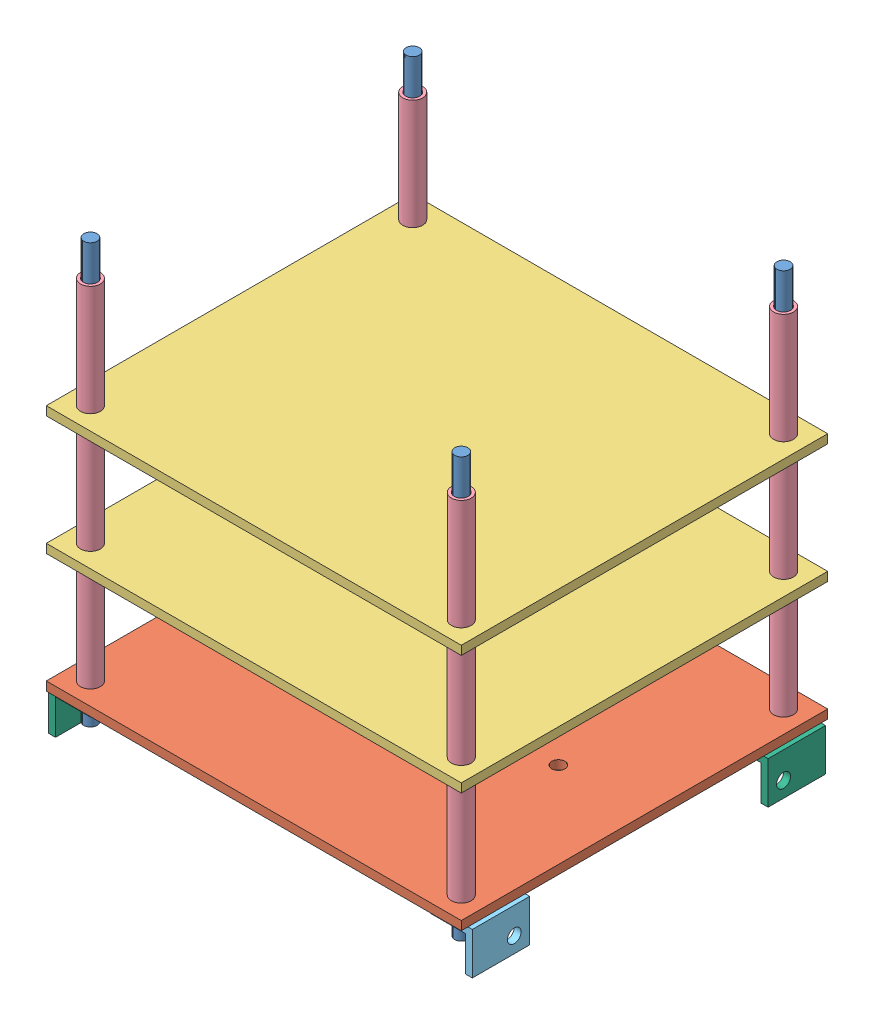
SolidWorks assembly PCB_Stack_3, configuration Default. Lengths in mm.
Overall size (96 98.53 83).
23 component instances, 6 part files, 64 mates.
Components (placement in the parent):
- PCB_Rod_2-1: PCB_Rod_2 [Default] at origin size (3 95 3)
- PCB_Rod_2-2: PCB_Rod_2 [Default] at (-84 0 0.0003) x (-0.139284 0 0.990253) z (-0.990253 0 -0.139284) size (3 95 3)
- PCB_Rod_2-3: PCB_Rod_2 [Default] at (-83.9998 0 73.0003) x (0.037489 0 0.999297) z (-0.999297 0 0.037489) size (3 95 3)
- PCB_Rod_2-4: PCB_Rod_2 [Default] at (0.0002 0 73) x (0.981991 0 -0.188925) z (0.188925 0 0.981991) size (3 95 3)
- PCB_Battery-1: PCB_Battery [Default] at (-41.9999 6 36.5001) x (-1 0 0.000003) z (-0.000003 0 -1) size (94 2 83)
- PCB-1: PCB [Default] at (-41.9999 60 36.5001) x (1 0 -0.000003) z (0.000003 0 1) size (94 2 83)
- PCB-2: PCB [Default] at (-41.9999 33 36.5001) x (1 0 -0.000003) z (0.000003 0 1) size (94 2 83)
- Aluminum Unthreaded Spacer_Battery-1: Aluminum Unthreaded Spacer_Battery [94669A105] at (0 20.5 0) x (0.317635 0 -0.948213) z (0 1 0) size (4.5 4.5 25)
- Aluminum Unthreaded Spacer_Battery-2: Aluminum Unthreaded Spacer_Battery [94669A105] at (0 47.5 0) x (0.317635 0 -0.948213) z (0 1 0) size (4.5 4.5 25)
- Aluminum Unthreaded Spacer_Battery-3: Aluminum Unthreaded Spacer_Battery [94669A105] at (0 74.5 0) x (-0.841831 0 -0.539741) z (0 1 0) size (4.5 4.5 25)
- Aluminum Unthreaded Spacer_Battery-4: Aluminum Unthreaded Spacer_Battery [94669A105] at (0.0002 20.5 73) x (0.317635 0 -0.948213) z (0 1 0) size (4.5 4.5 25)
- Aluminum Unthreaded Spacer_Battery-5: Aluminum Unthreaded Spacer_Battery [94669A105] at (0.0002 47.5 73) x (0.317635 0 -0.948213) z (0 1 0) size (4.5 4.5 25)
- Aluminum Unthreaded Spacer_Battery-6: Aluminum Unthreaded Spacer_Battery [94669A105] at (0.0002 74.5 73) x (-0.286549 0 -0.958066) z (0 1 0) size (4.5 4.5 25)
- Aluminum Unthreaded Spacer_Battery-7: Aluminum Unthreaded Spacer_Battery [94669A105] at (-83.9998 20.5 73.0003) x (0.317635 0 -0.948213) z (0 1 0) size (4.5 4.5 25)
- Aluminum Unthreaded Spacer_Battery-8: Aluminum Unthreaded Spacer_Battery [94669A105] at (-83.9998 47.5 73.0003) x (0.317635 0 -0.948213) z (0 1 0) size (4.5 4.5 25)
- Aluminum Unthreaded Spacer_Battery-9: Aluminum Unthreaded Spacer_Battery [94669A105] at (-83.9998 74.5 73.0003) x (-0.883236 0 -0.468929) z (0 1 0) size (4.5 4.5 25)
- Aluminum Unthreaded Spacer_Battery-10: Aluminum Unthreaded Spacer_Battery [94669A105] at (-84 47.5 0.0003) x (0.317635 0 -0.948213) z (0 1 0) size (4.5 4.5 25)
- Aluminum Unthreaded Spacer_Battery-11: Aluminum Unthreaded Spacer_Battery [94669A105] at (-84 74.5 0.0003) x (-0.872408 0 -0.488777) z (0 1 0) size (4.5 4.5 25)
- Aluminum Unthreaded Spacer_Battery-12: Aluminum Unthreaded Spacer_Battery [94669A105] at (-84 20.5 0.0003) x (0.317635 0 -0.948213) z (0 1 0) size (4.5 4.5 25)
- 88805K144_Architectural 6063 Aluminum 90 Degree Angle-1: 88805K144_Architectural 6063 Aluminum 90 Degree Angle [88805K144] at (-85.2375 1.2375 3.0003) x (-1 0 0.000003) z (0.000003 0 1) size (9.53 9.53 13)
- 88805K144_Architectural 6063 Aluminum 90 Degree Angle-2: 88805K144_Architectural 6063 Aluminum 90 Degree Angle [88805K144] at (1.2377 1.2375 70) x (0 1 0) z (0.000003 0 1) size (9.53 9.53 13)
- PCB_Bracket_1_(88805K144_Architectural 6063 Aluminum 90 Degree Angle)-1: PCB_Bracket_1_(88805K144_Architectural 6063 Aluminum 90 Degree Angle) [88805K144] at (1.2375 1.2375 3) x (0 1 0) z (0.000003 0 1) size (9.53 9.53 13)
- PCB_Bracket_1_(88805K144_Architectural 6063 Aluminum 90 Degree Angle)-2: PCB_Bracket_1_(88805K144_Architectural 6063 Aluminum 90 Degree Angle) [88805K144] at (-85.2373 1.2375 70.0003) x (0 1 0) z (-0.000003 0 -1) size (9.53 9.53 13)
Mates (geometry in assembly coordinates):
- Concentric1: concentric aligned: cylinder of PCB_Rod_2-1 through (0 95 0) axis (0 -1 0) radius 1.5; cylinder of PCB_Battery-1 through (0 7 0) axis (0 -1 0) radius 1.5
- Concentric2: concentric aligned: cylinder of PCB_Rod_2-4 through (0.0002 95 73) axis (0 -1 0) radius 1.5; cylinder of PCB_Battery-1 through (0.0002 7 73) axis (0 -1 0) radius 1.5
- Concentric3: concentric aligned: cylinder of PCB_Rod_2-3 through (-83.9998 95 73.0003) axis (0 -1 0) radius 1.5; cylinder of PCB_Battery-1 through (-83.9998 7 73.0003) axis (0 -1 0) radius 1.5
- Concentric4: concentric aligned: cylinder of PCB_Rod_2-2 through (-84 95 0.0003) axis (0 -1 0) radius 1.5; cylinder of PCB_Battery-1 through (-84 7 0.0003) axis (0 -1 0) radius 1.5
- Concentric10: concentric aligned: cylinder of PCB_Rod_2-2 through (-84 95 0.0003) axis (0 -1 0) radius 1.5; cylinder of PCB-2 through (-84 34 0.0003) axis (0 -1 0) radius 1.5
- Concentric11: concentric aligned: cylinder of PCB_Rod_2-3 through (-83.9998 95 73.0003) axis (0 -1 0) radius 1.5; cylinder of PCB-2 through (-83.9998 34 73.0003) axis (0 -1 0) radius 1.5
- Concentric12: concentric aligned: cylinder of PCB_Rod_2-1 through (0 95 0) axis (0 -1 0) radius 1.5; cylinder of PCB-2 through (0 34 0) axis (0 -1 0) radius 1.5
- Concentric13: concentric aligned: cylinder of PCB_Rod_2-4 through (0.0002 95 73) axis (0 -1 0) radius 1.5; cylinder of PCB-2 through (0.0002 34 73) axis (0 -1 0) radius 1.5
- Distance1: distance = 25 mm anti-aligned: plane of PCB-2 through (-41.9999 33 36.5001) normal (0 -1 0); plane of PCB_Battery-1 through (-41.9999 8 36.5001) normal (0 1 0)
- Concentric14: concentric aligned: cylinder of PCB_Rod_2-4 through (0.0002 95 73) axis (0 -1 0) radius 1.5; cylinder of PCB-1 through (0.0002 61 73) axis (0 -1 0) radius 1.5
- Concentric15: concentric aligned: cylinder of PCB_Rod_2-1 through (0 95 0) axis (0 -1 0) radius 1.5; cylinder of PCB-1 through (0 61 0) axis (0 -1 0) radius 1.5
- Distance2: distance = 25 mm anti-aligned: plane of PCB-1 through (-41.9999 60 36.5001) normal (0 -1 0); plane of PCB-2 through (-41.9999 35 36.5001) normal (0 1 0)
- Concentric16: concentric anti-aligned: cylinder of PCB_Rod_2-1 through (0 95 0) axis (0 -1 0) radius 1.5; cylinder of Mounting_Standoff-1 through (0 4 0) axis (0 1 0) radius 1.55
- Coincident1: coincident anti-aligned: plane of Mounting_Standoff-1 through (-41.9999 10 36.5001) normal (0 1 0); plane of PCB_Battery-1 through (-41.9999 5 36.5001) normal (0 -1 0)
- Parallel1: parallel aligned: plane of Mounting_Standoff-1 through (6 4 -7.5) normal (1 0 -0.000003); plane of PCB_Battery-1 through (5 7 -5) normal (1 0 -0.000003)
- Concentric17: concentric aligned: cylinder of PCB_Rod_2-2 through (-84 95 0.0003) axis (0 -1 0) radius 1.5; cylinder of Mounting_Standoff-2 through (-84 10 0.0003) axis (0 -1 0) radius 1.55
- Parallel3: parallel aligned: plane of PCB_Battery-1 through (-89 7 -4.9997) normal (-1 0 0.000003); plane of Mounting_Standoff-2 through (-90 10 -7.4997) normal (-1 0 0.000003)
- Coincident2: coincident anti-aligned: plane of PCB_Battery-1 through (-41.9999 5 36.5001) normal (0 -1 0); plane of Mounting_Standoff-2 through (-41.9999 10 36.5001) normal (0 1 0)
- Concentric18: concentric aligned: cylinder of PCB_Rod_2-4 through (0.0002 95 73) axis (0 -1 0) radius 1.5; cylinder of Mounting_Standoff-3 through (0.0002 10 73) axis (0 -1 0) radius 1.55
- Coincident3: coincident anti-aligned: plane of PCB_Battery-1 through (-41.9999 5 36.5001) normal (0 -1 0); plane of Mounting_Standoff-3 through (-41.9999 10 36.5001) normal (0 1 0)
- Parallel4: parallel aligned: plane of PCB_Battery-1 through (5.0003 7 78) normal (0.000003 0 1); plane of Mounting_Standoff-3 through (0.5003 10 80.5) normal (0.000003 0 1)
- Concentric19: concentric anti-aligned: cylinder of PCB_Rod_2-3 through (-83.9998 95 73.0003) axis (0 -1 0) radius 1.5; cylinder of Mounting_Standoff-4 through (-83.9998 4 73.0003) axis (0 1 0) radius 1.55
- Coincident5: coincident anti-aligned: plane of PCB_Battery-1 through (-41.9999 5 36.5001) normal (0 -1 0); plane of Mounting_Standoff-4 through (-41.9999 10 36.5001) normal (0 1 0)
- Parallel5: parallel aligned: plane of PCB_Battery-1 through (5.0003 7 78) normal (0.000003 0 1); plane of Mounting_Standoff-4 through (-84.4997 4 80.5003) normal (0.000003 0 1)
- Distance3: distance = 6 mm aligned: plane of PCB_Battery-1 through (-41.9999 6 36.5001) normal (0 -1 0); plane of PCB_Rod_2-1 through (0 0 0) normal (0 -1 0)
- Coincident6: coincident aligned: plane of PCB_Rod_2-1 through (0 0 0) normal (0 -1 0); plane of PCB_Rod_2-4 through (0.0002 0 73) normal (0 -1 0)
- Coincident7: coincident aligned: plane of PCB_Rod_2-1 through (0 0 0) normal (0 -1 0); plane of PCB_Rod_2-2 through (-84 0 0.0003) normal (0 -1 0)
- Coincident8: coincident aligned: plane of PCB_Rod_2-1 through (0 0 0) normal (0 -1 0); plane of PCB_Rod_2-3 through (-83.9998 0 73.0003) normal (0 -1 0)
- Concentric20: concentric aligned: cylinder of PCB_Rod_2-1 through (0 95 0) axis (0 -1 0) radius 1.5; cylinder of Aluminum Unthreaded Spacer_Battery-1 through (0 32 0) axis (0 -1 0) radius 1.6
- Coincident9: coincident anti-aligned: plane of PCB-2 through (-41.9999 32 36.5001) normal (0 -1 0); plane of Aluminum Unthreaded Spacer_Battery-1 through (0 32 0) normal (0 1 0)
- Concentric21: concentric aligned: cylinder of PCB_Rod_2-1 through (0 95 0) axis (0 -1 0) radius 1.5; cylinder of Aluminum Unthreaded Spacer_Battery-2 through (0 59 0) axis (0 -1 0) radius 1.6
- Coincident10: coincident anti-aligned: plane of PCB-1 through (-41.9999 59 36.5001) normal (0 -1 0); plane of Aluminum Unthreaded Spacer_Battery-2 through (0 59 0) normal (0 1 0)
- Concentric22: concentric aligned: cylinder of PCB_Rod_2-1 through (0 95 0) axis (0 -1 0) radius 1.5; cylinder of Aluminum Unthreaded Spacer_Battery-3 through (0 86 0) axis (0 -1 0) radius 1.6
- Coincident11: coincident anti-aligned: plane of PCB-1 through (-41.9999 61 36.5001) normal (0 1 0); plane of Aluminum Unthreaded Spacer_Battery-3 through (0 61 0) normal (0 -1 0)
- Concentric23: concentric aligned: cylinder of PCB_Rod_2-4 through (0.0002 95 73) axis (0 -1 0) radius 1.5; cylinder of Aluminum Unthreaded Spacer_Battery-4 through (0.0002 32 73) axis (0 -1 0) radius 1.6
- Coincident12: coincident anti-aligned: plane of PCB-2 through (-41.9999 32 36.5001) normal (0 -1 0); plane of Aluminum Unthreaded Spacer_Battery-4 through (0.0002 32 73) normal (0 1 0)
- Concentric24: concentric aligned: cylinder of PCB_Rod_2-4 through (0.0002 95 73) axis (0 -1 0) radius 1.5; cylinder of Aluminum Unthreaded Spacer_Battery-5 through (0.0002 59 73) axis (0 -1 0) radius 1.6
- Coincident13: coincident anti-aligned: plane of PCB-1 through (-41.9999 59 36.5001) normal (0 -1 0); plane of Aluminum Unthreaded Spacer_Battery-5 through (0.0002 59 73) normal (0 1 0)
- Concentric25: concentric aligned: cylinder of PCB_Rod_2-4 through (0.0002 95 73) axis (0 -1 0) radius 1.5; cylinder of Aluminum Unthreaded Spacer_Battery-6 through (0.0002 86 73) axis (0 -1 0) radius 1.6
- Coincident14: coincident anti-aligned: plane of PCB-1 through (-41.9999 61 36.5001) normal (0 1 0); plane of Aluminum Unthreaded Spacer_Battery-6 through (0.0002 61 73) normal (0 -1 0)
- Concentric26: concentric aligned: cylinder of PCB_Rod_2-3 through (-83.9998 95 73.0003) axis (0 -1 0) radius 1.5; cylinder of Aluminum Unthreaded Spacer_Battery-7 through (-83.9998 32 73.0003) axis (0 -1 0) radius 1.6
- Coincident15: coincident anti-aligned: plane of PCB-2 through (-41.9999 32 36.5001) normal (0 -1 0); plane of Aluminum Unthreaded Spacer_Battery-7 through (-83.9998 32 73.0003) normal (0 1 0)
- Concentric27: concentric aligned: cylinder of PCB_Rod_2-3 through (-83.9998 95 73.0003) axis (0 -1 0) radius 1.5; cylinder of Aluminum Unthreaded Spacer_Battery-8 through (-83.9998 59 73.0003) axis (0 -1 0) radius 1.6
- Coincident16: coincident anti-aligned: plane of PCB-1 through (-41.9999 59 36.5001) normal (0 -1 0); plane of Aluminum Unthreaded Spacer_Battery-8 through (-83.9998 59 73.0003) normal (0 1 0)
- Concentric28: concentric aligned: cylinder of PCB_Rod_2-3 through (-83.9998 95 73.0003) axis (0 -1 0) radius 1.5; cylinder of Aluminum Unthreaded Spacer_Battery-9 through (-83.9998 86 73.0003) axis (0 -1 0) radius 1.6
- Coincident17: coincident anti-aligned: plane of PCB-1 through (-41.9999 61 36.5001) normal (0 1 0); plane of Aluminum Unthreaded Spacer_Battery-9 through (-83.9998 61 73.0003) normal (0 -1 0)
- Concentric29: concentric aligned: cylinder of PCB_Rod_2-2 through (-84 95 0.0003) axis (0 -1 0) radius 1.5; cylinder of Aluminum Unthreaded Spacer_Battery-12 through (-84 32 0.0003) axis (0 -1 0) radius 1.6
- Coincident18: coincident anti-aligned: plane of PCB-2 through (-41.9999 32 36.5001) normal (0 -1 0); plane of Aluminum Unthreaded Spacer_Battery-12 through (-84 32 0.0003) normal (0 1 0)
- Concentric30: concentric aligned: cylinder of PCB_Rod_2-2 through (-84 95 0.0003) axis (0 -1 0) radius 1.5; cylinder of Aluminum Unthreaded Spacer_Battery-10 through (-84 59 0.0003) axis (0 -1 0) radius 1.6
- Coincident19: coincident anti-aligned: plane of PCB-1 through (-41.9999 59 36.5001) normal (0 -1 0); plane of Aluminum Unthreaded Spacer_Battery-10 through (-84 59 0.0003) normal (0 1 0)
- Concentric31: concentric aligned: cylinder of PCB_Rod_2-2 through (-84 95 0.0003) axis (0 -1 0) radius 1.5; cylinder of Aluminum Unthreaded Spacer_Battery-11 through (-84 86 0.0003) axis (0 -1 0) radius 1.6
- Coincident20: coincident anti-aligned: plane of PCB-1 through (-41.9999 61 36.5001) normal (0 1 0); plane of Aluminum Unthreaded Spacer_Battery-11 through (-84 61 0.0003) normal (0 -1 0)
- Concentric33: concentric anti-aligned: cylinder of PCB_Rod_2-2 through (-84 95 0.0003) axis (0 -1 0) radius 1.5; circle of 88805K144_Architectural 6063 Aluminum 90 Degree Angle-1
- Coincident22: coincident anti-aligned: plane of PCB_Battery-1 through (-41.9999 5 36.5001) normal (0 -1 0); plane of 88805K144_Architectural 6063 Aluminum 90 Degree Angle-1 through (-80.475 5 9.5003) normal (0 1 0)
- Parallel6: parallel anti-aligned: line of PCB_Battery-1 through (-89 5 -4.9997) axis (0.000003 0 1); line of 88805K144_Architectural 6063 Aluminum 90 Degree Angle-1 through (-90 5 9.5003) axis (-0.000003 0 -1)
- Concentric34: concentric anti-aligned: cylinder of PCB_Rod_2-4 through (0.0002 95 73) axis (0 -1 0) radius 1.5; circle of 88805K144_Architectural 6063 Aluminum 90 Degree Angle-2
- Coincident24: coincident anti-aligned: plane of PCB_Battery-1 through (-41.9999 5 36.5001) normal (0 -1 0); plane of 88805K144_Architectural 6063 Aluminum 90 Degree Angle-2 through (6.0002 5 76.5) normal (0 1 0)
- Parallel7: parallel aligned: line of PCB_Battery-1 through (5.0003 5 78) axis (-0.000003 0 -1); line of 88805K144_Architectural 6063 Aluminum 90 Degree Angle-2 through (6.0002 5 76.5) axis (-0.000003 0 -1)
- Concentric35: concentric anti-aligned: cylinder of PCB_Rod_2-1 through (0 95 0) axis (0 -1 0) radius 1.5; circle of PCB_Bracket_1_(88805K144_Architectural 6063 Aluminum 90 Degree Angle)-1
- Coincident26: coincident anti-aligned: plane of PCB_Battery-1 through (-41.9999 5 36.5001) normal (0 -1 0); plane of PCB_Bracket_1_(88805K144_Architectural 6063 Aluminum 90 Degree Angle)-1 through (6 5 9.5) normal (0 1 0)
- Parallel8: parallel aligned: line of PCB_Battery-1 through (5.0003 5 78) axis (-0.000003 0 -1); line of PCB_Bracket_1_(88805K144_Architectural 6063 Aluminum 90 Degree Angle)-1 through (6 5 9.5) axis (-0.000003 0 -1)
- Concentric36: concentric anti-aligned: cylinder of PCB_Rod_2-3 through (-83.9998 95 73.0003) axis (0 -1 0) radius 1.5; cylinder of PCB_Bracket_1_(88805K144_Architectural 6063 Aluminum 90 Degree Angle)-2 through (-83.9998 -5 73.0003) axis (0 1 0) radius 1.5875
- Coincident28: coincident anti-aligned: plane of PCB_Battery-1 through (-41.9999 5 36.5001) normal (0 -1 0); plane of PCB_Bracket_1_(88805K144_Architectural 6063 Aluminum 90 Degree Angle)-2 through (-89.9998 5 63.5003) normal (0 1 0)
- Parallel9: parallel aligned: line of PCB_Battery-1 through (-89 5 -4.9997) axis (0.000003 0 1); line of PCB_Bracket_1_(88805K144_Architectural 6063 Aluminum 90 Degree Angle)-2 through (-89.9998 5 63.5003) axis (0.000003 0 1)
